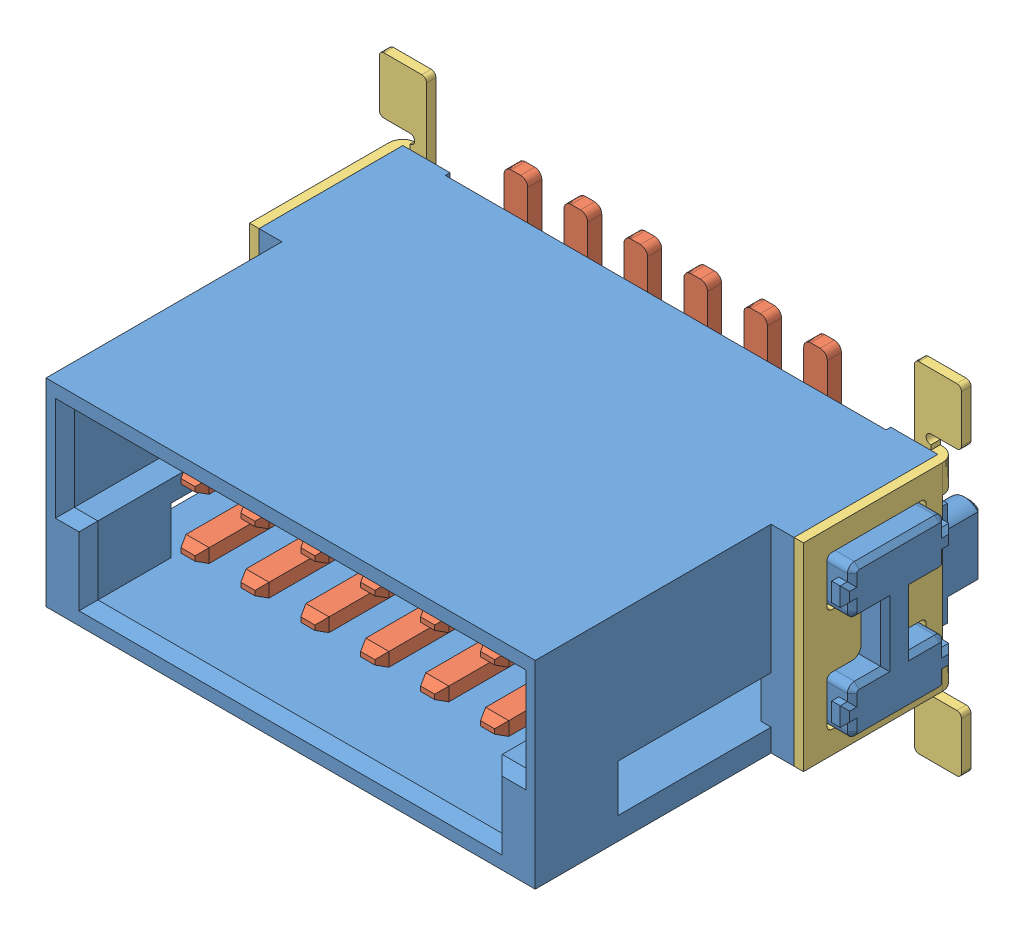
SolidWorks assembly m55-7011242_asm, configuration Default. Lengths in mm.
Overall size (12.7 7.2 9).
16 component instances, 3 part files, 0 mates.
Components (placement in the parent):
- m55-7011242_asm.stp-1: m55-7011242_asm.stp [Default] at origin size (12.7 7.2 9)
  - M55-70112_MOULD.stp-1: M55-70112_MOULD.stp [Default] at origin size (12.7 4.2 9)
  - M55-701_CONTACT.stp-1: M55-701_CONTACT.stp [Default] at (-3.175 -0.785 7.25) x (1 0 0) z (0 1 0) size (1.1 7.25 2.42)
  - M55-701_CONTACT.stp-2: M55-701_CONTACT.stp [Default] at (-1.905 -0.785 7.25) x (1 0 0) z (0 1 0) size (1.1 7.25 2.42)
  - M55-701_CONTACT.stp-3: M55-701_CONTACT.stp [Default] at (-0.635 -0.785 7.25) x (1 0 0) z (0 1 0) size (1.1 7.25 2.42)
  - M55-701_CONTACT.stp-4: M55-701_CONTACT.stp [Default] at (0.635 -0.785 7.25) x (1 0 0) z (0 1 0) size (1.1 7.25 2.42)
  - M55-701_CONTACT.stp-5: M55-701_CONTACT.stp [Default] at (1.905 -0.785 7.25) x (1 0 0) z (0 1 0) size (1.1 7.25 2.42)
  - M55-701_CONTACT.stp-6: M55-701_CONTACT.stp [Default] at (3.175 -0.785 7.25) x (1 0 0) z (0 1 0) size (1.1 7.25 2.42)
  - M55-701_CONTACT.stp-7: M55-701_CONTACT.stp [Default] at (-3.175 0.785 7.25) x (-1 0 0) z (0 -1 0) size (1.1 7.25 2.42)
  - M55-701_CONTACT.stp-8: M55-701_CONTACT.stp [Default] at (-1.905 0.785 7.25) x (-1 0 0) z (0 -1 0) size (1.1 7.25 2.42)
  - M55-701_CONTACT.stp-9: M55-701_CONTACT.stp [Default] at (-0.635 0.785 7.25) x (-1 0 0) z (0 -1 0) size (1.1 7.25 2.42)
  - M55-701_CONTACT.stp-10: M55-701_CONTACT.stp [Default] at (0.635 0.785 7.25) x (-1 0 0) z (0 -1 0) size (1.1 7.25 2.42)
  - M55-701_CONTACT.stp-11: M55-701_CONTACT.stp [Default] at (1.905 0.785 7.25) x (-1 0 0) z (0 -1 0) size (1.1 7.25 2.42)
  - M55-701_CONTACT.stp-12: M55-701_CONTACT.stp [Default] at (3.175 0.785 7.25) x (-1 0 0) z (0 -1 0) size (1.1 7.25 2.42)
  - M55-700_STRAP.stp-1: M55-700_STRAP.stp [Default] at (-5.67 0 0) x (1 0 0) z (0 -1 0) size (1 3.25 7.2)
  - M55-700_STRAP.stp-2: M55-700_STRAP.stp [Default] at (5.67 0 0) x (-1 0 0) z (0 1 0) size (1 3.25 7.2)
